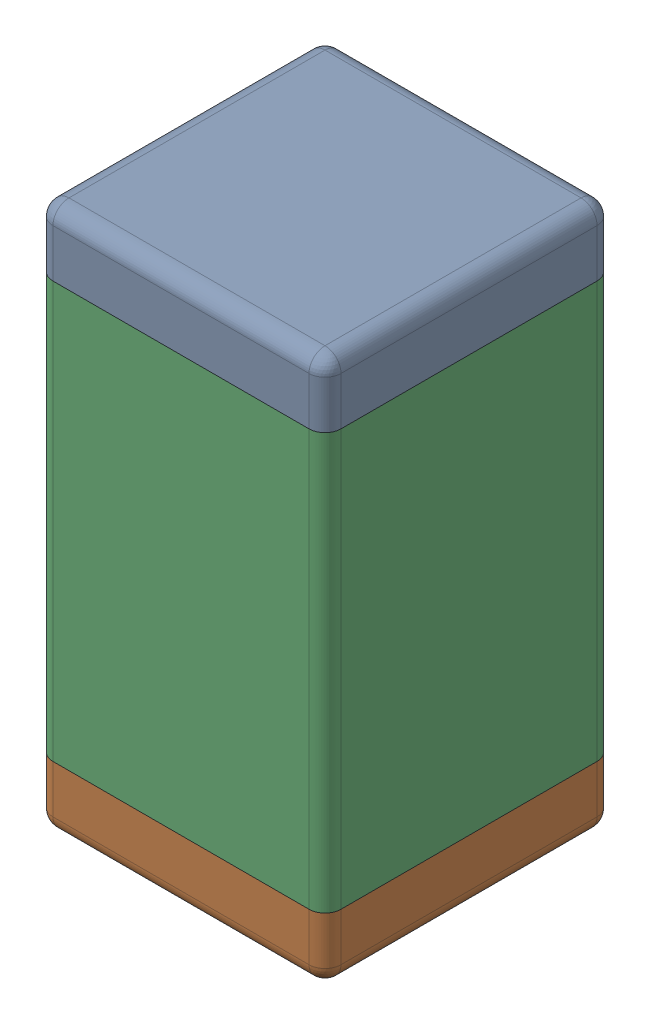
SolidWorks assembly C4, configuration Default. Lengths in mm.
Overall size (0.9 1.7 0.9).
6 component instances, 3 part files, 0 mates.
Components (placement in the parent):
- 5943011504-1: 5943011504 [Default] at (25.265 4.445 0) x (0 -1 0) z (0 0 1) size (1.7 0.9 0.9)
  - Terminal_3-1: Terminal_3 [Default] at (-0.85 -0.45 0) size (1.7 0.9 0.9)
    - Open CASCADE STEP translator 6.8 6.1.1-1: Open CASCADE STEP translator 6.8 6.1.1 [Default] at origin size (0.2 0.9 0.9)
    - Open CASCADE STEP translator 6.8 6.1.2-1: Open CASCADE STEP translator 6.8 6.1.2 [Default] at origin size (0.2 0.9 0.9)
  - Mid_Body-1: Mid_Body [Default] at (-0.85 -0.45 0) size (1.3 0.9 0.9)
    - Open CASCADE STEP translator 6.8 6.2.1-1: Open CASCADE STEP translator 6.8 6.2.1 [Default] at origin size (1.3 0.9 0.9)
